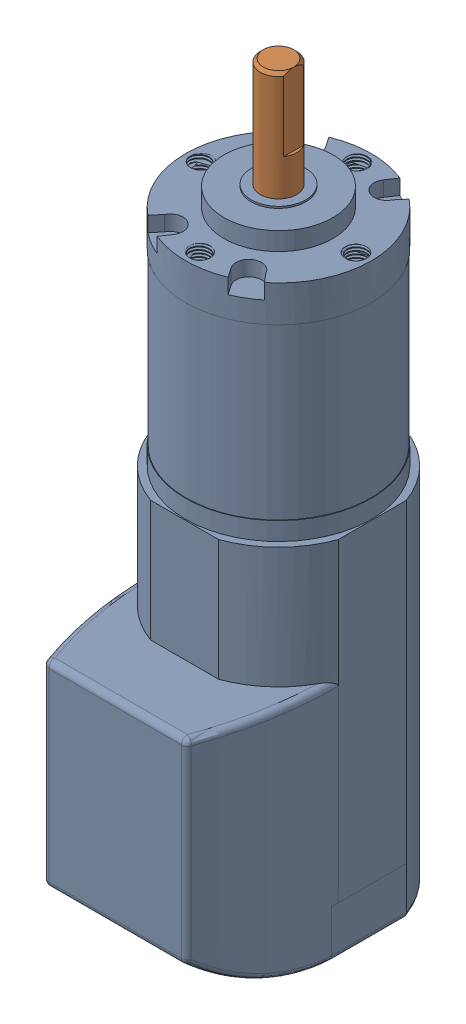
SolidWorks assembly Motor_v1, configuration Default. Lengths in mm.
Overall size (32.95 119.37 42.5).
2 component instances, 2 part files, 2 mates.
Components (placement in the parent):
- Motor_NEW-1: Motor_NEW [Default] at (-50.0322 20.4938 13.7973) size (32.95 101.37 42.5)
- MOTOR SHAFT-1: MOTOR SHAFT [Default] at (-50.0322 60.7938 13.7973) x (1 0 0) z (0 1 0) size (6 6 18)
Mates (geometry in assembly coordinates):
- Coincident4: coincident: plane of Motor_NEW-1 through (-50.0322 60.7938 13.7973) normal (0 1 0); plane of MOTOR SHAFT-1 through (-62.237 60.7938 -7.8513) normal (0 -1 0)
- Concentric1: concentric aligned: cylinder of Motor_NEW-1 through (-50.0322 60.7938 13.7973) axis (0 -1 0) radius 4.5; cylinder of MOTOR SHAFT-1 through (-50.0322 78.7938 13.7973) axis (0 -1 0) radius 3
